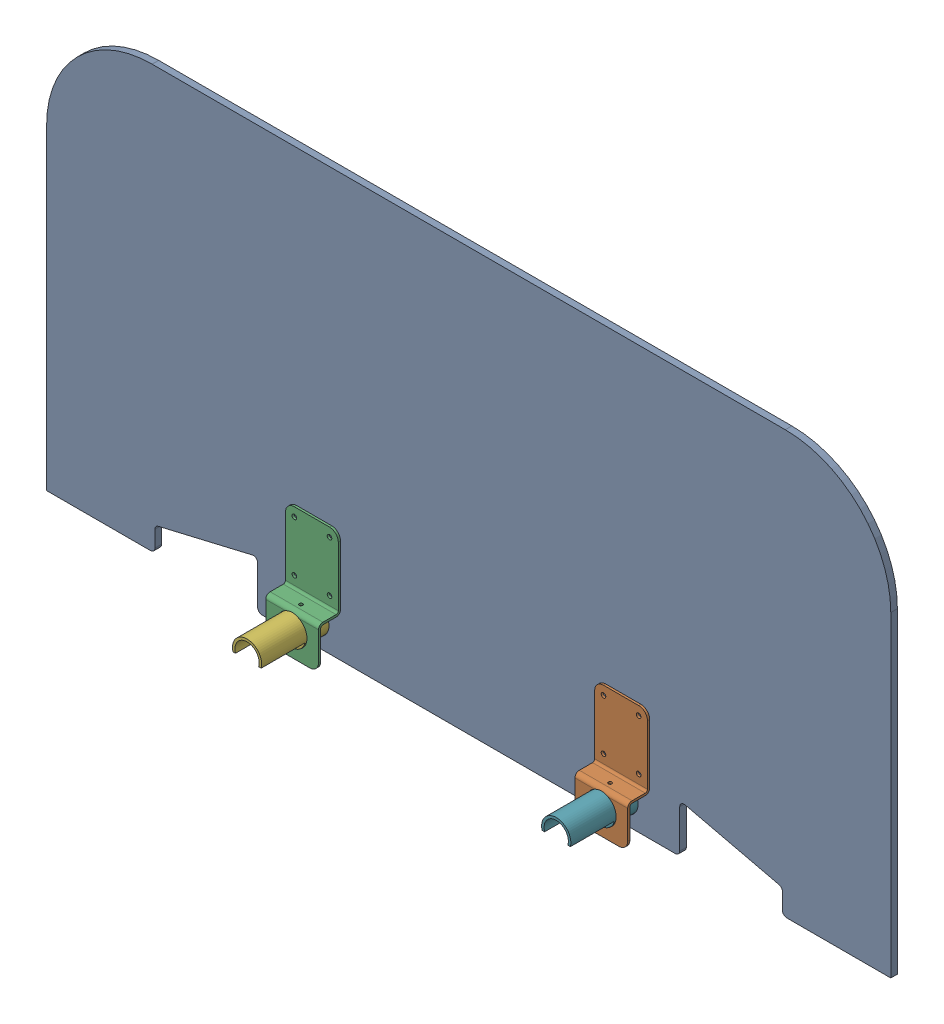
SolidWorks assembly GE-16023_ASM, configuration Default. Lengths in mm.
Overall size (1219.2 609.6 203.2).
7 component instances, 3 part files, 0 mates.
Components (placement in the parent):
- GE-16020-1: GE-16020 [Default] at origin size (1219.2 609.6 9.53)
- GE-16021-1: GE-16021 [Default] at (223.266 -304.8 36.5125) x (1 0 0) z (0 -1 0) size (76.2 31.77 161.93)
- GE-16021-2: GE-16021 [Default] at (-223.266 -304.8 36.5125) x (1 0 0) z (0 -1 0) size (76.2 31.77 161.93)
- GE-16021-3: GE-16021 [Default] at (223.266 -304.8 -36.5125) x (-1 0 0) z (0 -1 0) size (76.2 31.77 161.93)
- GE-16021-4: GE-16021 [Default] at (-223.266 -304.8 -36.5125) x (-1 0 0) z (0 -1 0) size (76.2 31.77 161.93)
- GE-16024-1: GE-16024 [Default] at (-223.266 -269.875 0) x (0 0 -1) z (0 -1 0) size (203.2 42.16 42.16)
- GE-16024-2: GE-16024 [Default] at (223.266 -269.875 0) x (0 0 -1) z (0 -1 0) size (203.2 42.16 42.16)
